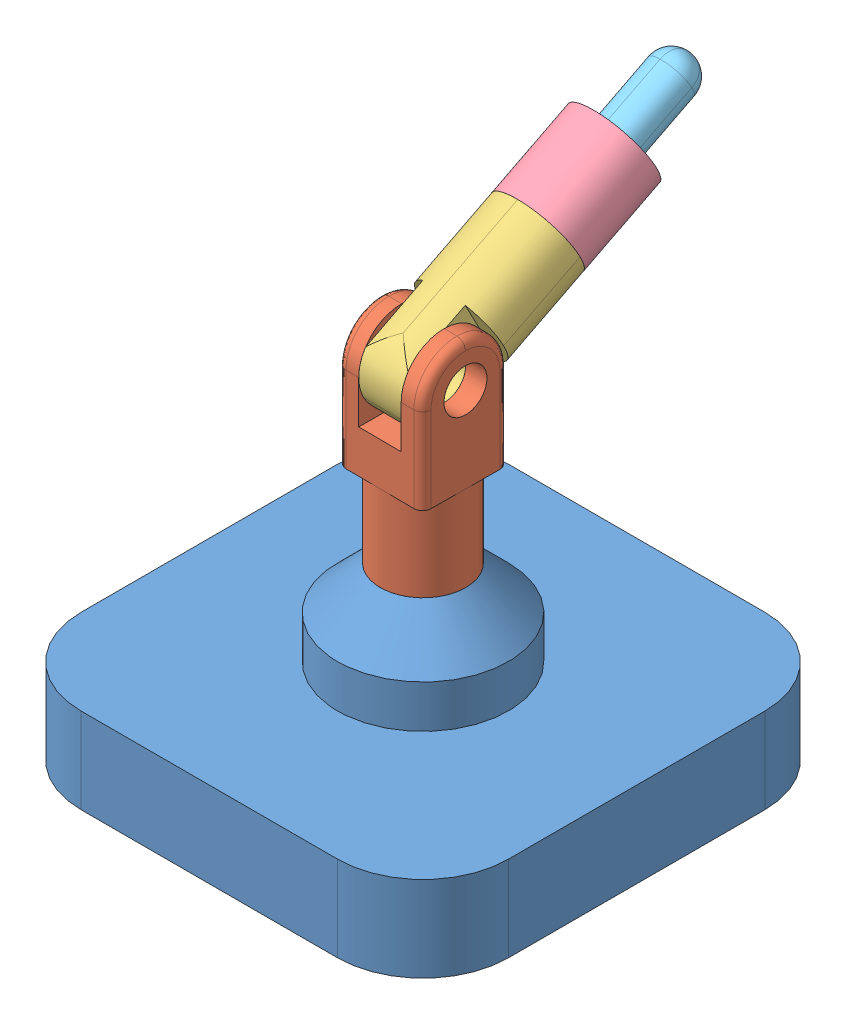
SolidWorks assembly assembly, configuration Default. Lengths in mm.
Overall size (500 585.04 572.98).
5 component instances, 5 part files, 25 mates.
Components (placement in the parent):
- link_0-2: link_0 [Default] at (-71.7752 -62.4193 637.9223) size (500 300 500)
- link_1-1: link_1 [Default] at (-71.7752 237.5807 637.9223) x (-0.007472 0 0.999972) z (-0.999972 0 -0.007472) size (100 250 100)
- link_2-1: link_2 [Default] at (-21.4451 360.6428 593.9335) x (0.00663 0.461243 -0.887249) z (-0.003447 0.887274 0.46123) size (200 100 100)
- link_3-2: link_3 [Default] at (-70.7807 406.7672 504.835) x (-0.069859 0.885314 0.459715) z (-0.997535 -0.058934 -0.038092) size (100 100 100)
- link_4-2: link_4 [Default] at (-70.1177 452.8915 416.1101) x (-0.069859 0.885314 0.459715) z (-0.997535 -0.058934 -0.038092) size (50 200 50)
Mates (geometry in assembly coordinates):
- Concentric1: concentric anti-aligned: cylinder of base_link-1 through (-71.7752 237.5807 637.9223) axis (0 -1 0) radius 25; cylinder of link_0-1 through (-71.7752 137.5807 637.9223) axis (0 1 0) radius 25
- Coincident1: coincident anti-aligned: plane of base_link-1 through (-71.7752 137.5807 637.9223) normal (0 1 0); plane of link_0-1 through (-71.7752 137.5807 637.9223) normal (0 -1 0)
- Concentric2: concentric anti-aligned: cylinder of link_0-1 through (-104.5114 337.5807 675.7157) axis (0.654725 0 -0.755867) radius 25; cylinder of link_4-1 through (-100.6234 437.5807 678.7608) axis (0.576964 0 -0.816769) radius 25
- Coincident2: coincident anti-aligned: plane of link_0-1 through (-50.3499 287.5807 689.5552) normal (0.654725 0 -0.755867); plane of link_4-1
- Concentric3: concentric anti-aligned: cylinder of link_2-1 through (-121.7738 337.5807 637.5487) axis (0.999972 0 0.007472) radius 25; cylinder of link_4-1 through (63.3725 895.4944 794.6072) axis (0.576964 0 -0.816769) radius 25
- Coincident3: coincident anti-aligned: plane of link_2-1 through (-46.6167 405.0065 616.8082) normal (0.999972 0 0.007472); plane of link_4-1 through (98.798 829.6244 789.0233) normal (0.576964 0 -0.816769)
- Coincident4: coincident anti-aligned: plane of link_2-1 through (-120.607 362.4035 481.3998) normal (0.00663 0.461243 -0.887249); plane of link_3-1 through (-14.1687 587.5082 596.6521) normal (-0.611649 -0.787186 -0.07889)
- Concentric4: concentric anti-aligned: cylinder of link_2-1 through (-71.4437 360.6428 593.5599) axis (-0.00663 -0.461243 0.887249) radius 50; cylinder of link_3-1 through (142.3021 713.0957 665.5337) axis (0.611649 0.787186 0.07889) radius 50
- Concentric5: concentric anti-aligned: cylinder of link_1-1 through (235.2552 957.9607 1042.146) axis (0.40459 -0.880009 -0.248777) radius 25; cylinder of link_3-1 through (116.8067 674.7675 611.8594) axis (-0.101742 -0.020622 0.994597) radius 25
- Coincident5: coincident anti-aligned: plane of link_1-1 through (282.452 935.9886 1096.1339) normal (0.40459 -0.880009 -0.248777); plane of link_3-1 through (117.8216 603.0431 685.8835) normal (-0.101742 -0.020622 0.994597)
- Concentric6: concentric anti-aligned: cylinder of link_1-1 through (155.7855 790.1793 1506.4023) axis (0.40459 -0.880009 -0.248777) radius 25; cylinder of link_5-1 through (116.8067 674.7675 611.8594) axis (-0.101742 -0.020622 0.994597) radius 25
- Coincident6: coincident anti-aligned: plane of link_1-1 through (128.8182 768.1509 1439.9756) normal (-0.40459 0.880009 0.248777); plane of link_5-1 through (158.9162 672.9107 691.5359) normal (0.101742 0.020622 -0.994597)
- Concentric7: concentric aligned: cylinder of link_0-1 through (-104.5114 337.5807 675.7157) axis (0.654725 0 -0.755867) radius 25; cylinder of link_2-1 through (-121.7738 337.5807 637.5487) axis (0.999972 0 0.007472) radius 25
- Coincident7: coincident anti-aligned: plane of link_0-1; plane of link_2-1 through (-46.6167 405.0065 616.8082) normal (0.999972 0 0.007472)
- Concentric8: concentric aligned: cylinder of link_3-1 through (116.8067 674.7675 611.8594) axis (-0.101742 -0.020622 0.994597) radius 25; cylinder of link_5-1 through (116.8067 674.7675 611.8594) axis (-0.101742 -0.020622 0.994597) radius 25
- Coincident8: coincident anti-aligned: plane of link_3-1 through (117.8216 603.0431 685.8835) normal (-0.101742 -0.020622 0.994597); plane of link_5-1 through (158.9162 672.9107 691.5359) normal (0.101742 0.020622 -0.994597)
- Coincident9: coincident anti-aligned: plane of link_2-1 through (-120.607 362.4035 481.3998) normal (0.00663 0.461243 -0.887249); plane of link_3-2 through (-70.7807 406.7672 504.835) normal (-0.00663 -0.461243 0.887249)
- Concentric9: concentric anti-aligned: cylinder of link_2-1 through (-72.1067 314.5185 682.2848) axis (0.00663 0.461243 -0.887249) radius 50; cylinder of link_3-2 through (-70.1177 452.8915 416.1101) axis (-0.00663 -0.461243 0.887249) radius 50
- Coincident12: coincident anti-aligned: plane of link_3-2 through (-56.7752 442.5617 410.8398) normal (-0.997535 -0.058934 -0.038092); plane of link_5-2 through (-57.4383 396.4374 499.5647) normal (0.997535 0.058934 0.038092)
- Coincident13: coincident anti-aligned: plane of link_3-2 through (-58.5217 464.6946 422.3327) normal (0.069859 -0.885314 -0.459715); plane of link_5-2 through (-84.1231 417.0969 510.1053) normal (-0.069859 0.885314 0.459715)
- LimitDistance3: limit distance = 0 mm anti-aligned: plane of link_3-2 through (-70.1177 452.8915 416.1101) normal (0.00663 0.461243 -0.887249); plane of link_5-2 through (-70.1177 452.8915 416.1101) normal (-0.00663 -0.461243 0.887249)
- Concentric10: concentric anti-aligned: cylinder of link_0-2 through (-71.7752 237.5807 637.9223) axis (0 -1 0) radius 25; cylinder of link_1-1 through (-71.7752 137.5807 637.9223) axis (0 1 0) radius 50
- Coincident14: coincident anti-aligned: plane of link_0-2 through (-71.7752 137.5807 637.9223) normal (0 1 0); plane of link_1-1 through (-71.7752 137.5807 637.9223) normal (0 -1 0)
- Coincident15: coincident anti-aligned: plane of link_2-1 through (-46.6167 405.0065 616.8082) normal (0.999972 0 0.007472); plane of link_1-1 through (-46.4023 287.5807 588.1105) normal (-0.999972 0 -0.007472)
- Concentric11: concentric anti-aligned: cylinder of link_2-1 through (-121.7738 337.5807 637.5487) axis (0.999972 0 0.007472) radius 25; cylinder of link_1-1 through (-21.7766 337.5807 638.2959) axis (-0.999972 0 -0.007472) radius 25
